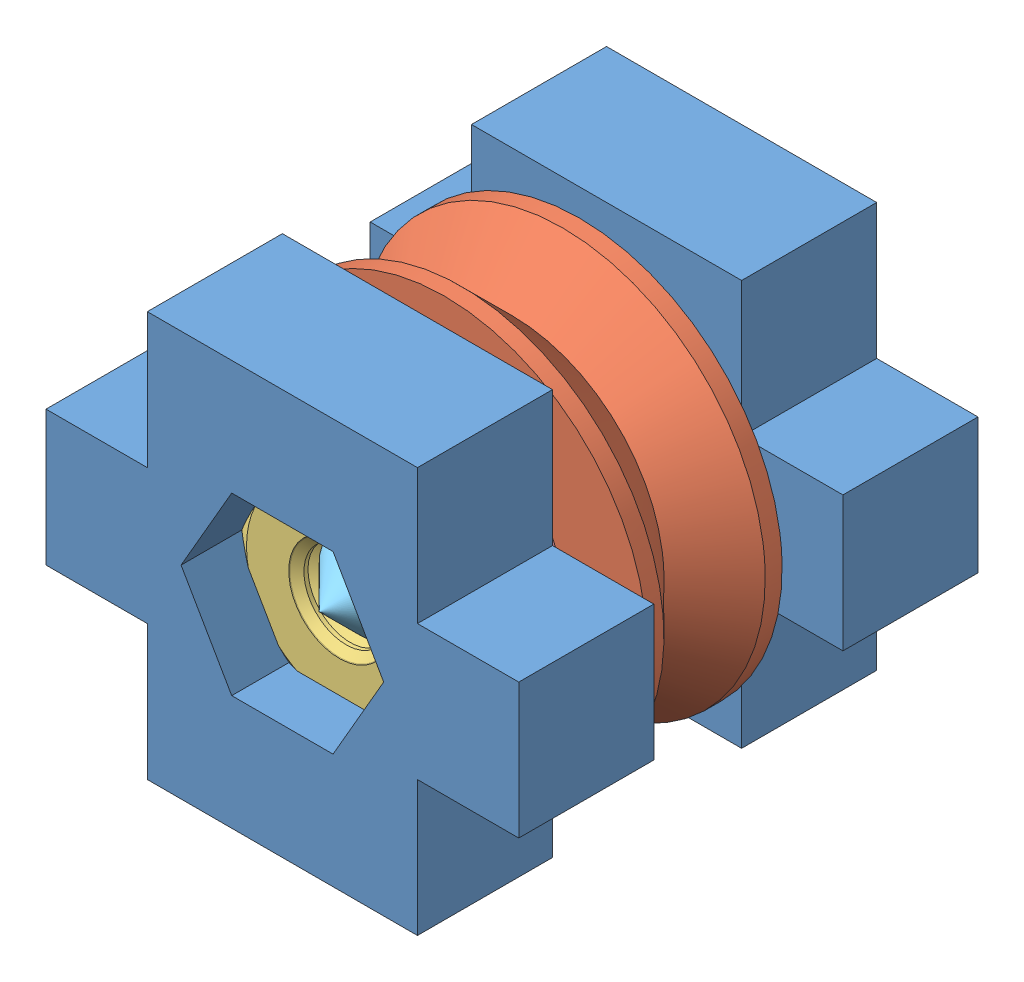
SolidWorks assembly pulleyInsidePalmAssembled, configuration Default. Lengths in mm.
Overall size (14 13.03 13.6).
8 component instances, 5 part files, 18 mates.
Components (placement in the parent):
- BasePulleyInsidePalm-1: BasePulleyInsidePalm [Default] at (-0.6961 4.81 7.3798) size (14 12 4)
- BasePulleyInsidePalm-2: BasePulleyInsidePalm [Default] at (-0.6961 4.81 16.9798) size (14 12 4)
- pulley-1: pulley [Default] at (3.3039 10.81 12.1798) x (0.995915 0.090298 0) z (0 0 1) size (12 12 4)
- hex nut style 1 gradeab_din-2: hex nut style 1 gradeab_din [Hexagon Nut ISO 4032 - M3 - D - S] at (3.3916 10.6581 19.3798) x (0.866025 -0.5 0) z (0 0 1) size (5.5 6.35 2.4)
- hex nut style 1 gradeab_din-3: hex nut style 1 gradeab_din [Hexagon Nut ISO 4032 - M3 - D - S] at (3.2162 10.6581 10.3798) x (0.866025 -0.5 0) z (0 0 1) size (5.5 6.35 2.4)
- plain washer 6902 type abc_din-1: plain washer 6902 type abc_din [DIN 6902-C3.2] at (3.3039 10.81 16.9798) x (0 0 -1) z (0.829839 0.558003 0) size (0.8 7 7)
- plain washer 6902 type abc_din-2: plain washer 6902 type abc_din [DIN 6902-C3.2] at (3.3039 10.81 11.3798) x (0 0 1) z (-1 0 0) size (0.8 7 7)
- slotted set screw cone point_din-1: slotted set screw cone point_din [ISO 7434 - M3 x 12-S] at (3.3916 10.6581 7.9798) x (0 0 1) z (-0.968704 -0.248217 0) size (12 3 3)
Mates (geometry in assembly coordinates):
- Coincident1: coincident aligned: plane of BasePulleyInsidePalm-1 through (-3.6961 12.81 11.3798) normal (-1 0 0); plane of BasePulleyInsidePalm-2 through (-3.6961 12.81 20.9798) normal (-1 0 0)
- Coincident2: coincident aligned: plane of BasePulleyInsidePalm-1 through (7.3039 16.81 11.3798) normal (0 1 0); plane of BasePulleyInsidePalm-2 through (7.3039 16.81 20.9798) normal (0 1 0)
- Distance1: distance = 5.6 mm anti-aligned: plane of BasePulleyInsidePalm-1 through (-0.6961 4.81 11.3798) normal (0 0 1); plane of BasePulleyInsidePalm-2 through (-0.6961 4.81 16.9798) normal (0 0 -1)
- Distance2: distance = 1.5 mm: line of BasePulleyInsidePalm-1 through (6.3039 10.81 11.3798) axis (0 0 -1); cylinder of pulley-1 through (3.3039 10.81 14.1798) axis (0 0 -1) radius 1.5
- Distance3: distance = 1.5 mm: cylinder of pulley-1 through (3.3039 10.81 14.1798) axis (0 0 -1) radius 1.5; line of BasePulleyInsidePalm-1 through (0.3039 10.81 11.3798) axis (0 0 -1)
- Distance4: distance = 0.8 mm anti-aligned: plane of pulley-1 through (3.3039 10.81 12.1798) normal (0 0 -1); plane of BasePulleyInsidePalm-1 through (-0.6961 4.81 11.3798) normal (0 0 1)
- Coincident7: coincident anti-aligned: plane of BasePulleyInsidePalm-2 through (1.8039 13.4081 20.9798) normal (0.866025 -0.5 0); plane of hex nut style 1 gradeab_din-2 through (1.8039 13.4081 16.9798) normal (-0.866025 0.5 0)
- Distance5: distance = 0.8 mm anti-aligned: plane of pulley-1 through (3.3039 10.81 16.1798) normal (0 0 1); plane of hex nut style 1 gradeab_din-2 through (4.9793 13.4081 16.9798) normal (0 0 -1)
- Coincident12: coincident anti-aligned: plane of BasePulleyInsidePalm-2 through (4.8039 13.4081 20.9798) normal (0 -1 0); plane of hex nut style 1 gradeab_din-2 through (4.9793 13.4081 16.9798) normal (0 1 0)
- Coincident13: coincident anti-aligned: plane of BasePulleyInsidePalm-1 through (6.3039 10.81 11.3798) normal (-0.866025 -0.5 0); plane of hex nut style 1 gradeab_din-3 through (6.3916 10.6581 7.9798) normal (0.866025 0.5 0)
- Coincident14: coincident anti-aligned: plane of BasePulleyInsidePalm-1 through (4.8039 13.4081 11.3798) normal (0 -1 0); plane of hex nut style 1 gradeab_din-3 through (4.8039 13.4081 7.9798) normal (0 1 0)
- Distance6: distance = 3 mm anti-aligned: plane of BasePulleyInsidePalm-1 through (-0.6961 4.81 7.3798) normal (0 0 -1); plane of hex nut style 1 gradeab_din-3 through (4.8039 13.4081 10.3798) normal (0 0 1)
- Concentric10: concentric anti-aligned: cylinder of pulley-1 through (3.3039 10.81 14.1798) axis (0 0 -1) radius 1.5; cylinder of plain washer 6902 type abc_din-1 through (3.3039 10.81 16.1798) axis (0 0 1) radius 1.6
- Coincident15: coincident anti-aligned: plane of BasePulleyInsidePalm-2 through (-0.6961 4.81 16.9798) normal (0 0 -1); plane of plain washer 6902 type abc_din-1 through (3.3039 10.81 16.9798) normal (0 0 1)
- Coincident16: coincident anti-aligned: plane of pulley-1 through (3.3039 10.81 12.1798) normal (0 0 -1); plane of plain washer 6902 type abc_din-2 through (3.3039 10.81 12.1798) normal (0 0 1)
- Concentric11: concentric aligned: cylinder of pulley-1 through (3.3039 10.81 14.1798) axis (0 0 -1) radius 1.5; cylinder of plain washer 6902 type abc_din-2 through (3.3039 10.81 12.1798) axis (0 0 -1) radius 1.6
- Concentric12: concentric anti-aligned: circle of hex nut style 1 gradeab_din-2; circle of slotted set screw cone point_din-1
- Coincident18: coincident aligned: plane of hex nut style 1 gradeab_din-3 through (4.8039 13.4081 7.9798) normal (0 0 -1); plane of slotted set screw cone point_din-1 through (3.3916 10.6581 7.9798) normal (0 0 -1)
